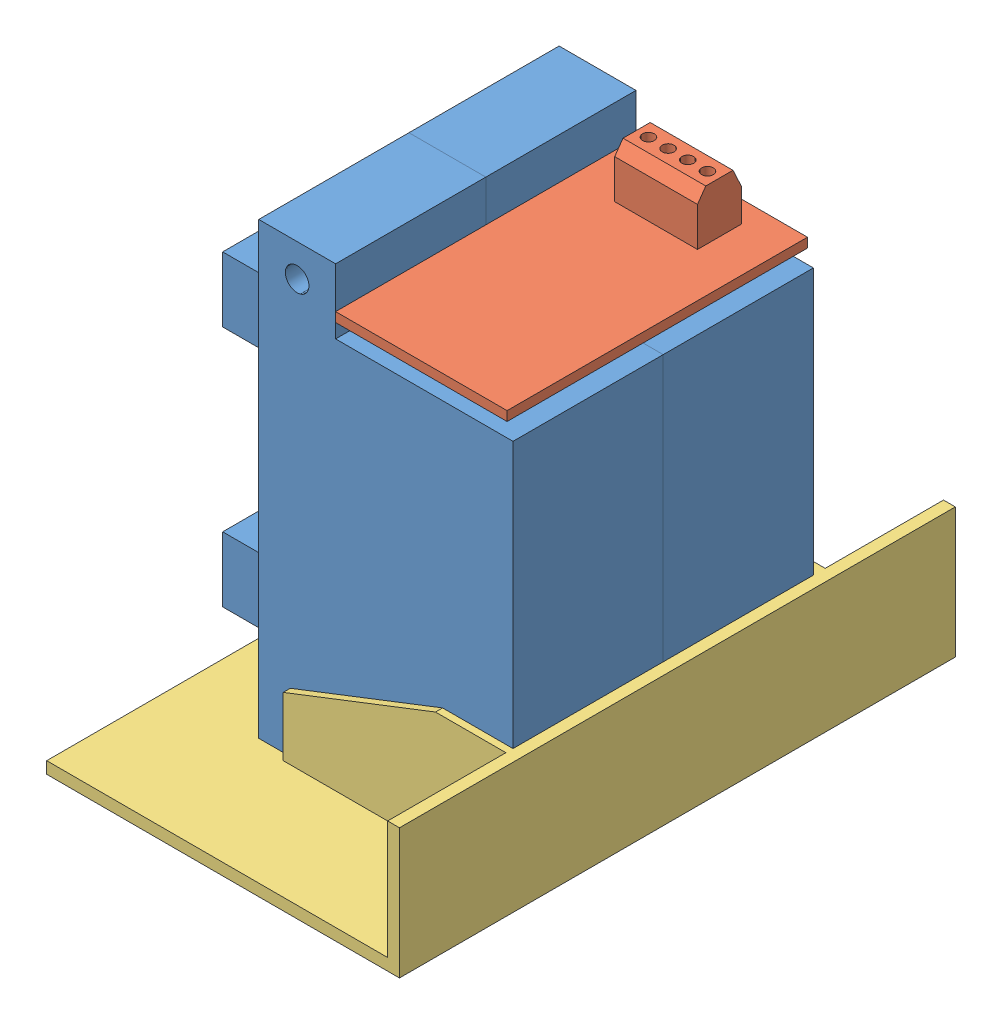
SolidWorks assembly 123SmartRelay, configuration Predeterminado. Lengths in mm.
Overall size (59.66 79.6 94).
4 component instances, 3 part files, 9 mates.
Components (placement in the parent):
- Relay200A-1: Relay200A [Predeterminado] at origin size (53.3 76 25.4)
- Relay200A-2: Relay200A [Predeterminado] at (0 0 -25.4) size (53.3 76 25.4)
- PCB_relays-1: PCB_relays [Predeterminado] at (27.5 67.4 -12.7) size (29 10.2 50.8)
- base relay-1: base relay [Predeterminado] at (43 0 -13.1) x (0 0 -1) z (1 0 0) size (94 22 59.66)
Mates (geometry in assembly coordinates):
- Coincidente1: coincident: plane of Relay200A-1 through (43 0 12.7) normal (1 0 0); plane of Relay200A-2 through (43 0 -12.7) normal (1 0 0)
- Coincidente2: coincident: plane of Relay200A-1 through (0 0 -12.7) normal (0 0 -1); plane of Relay200A-2 through (0 0 -12.7) normal (0 0 1)
- Coincidente3: coincident aligned: plane of Relay200A-1 through (0 0 12.7) normal (0 -1 0); plane of Relay200A-2 through (0 0 -12.7) normal (0 -1 0)
- Coincidente4: coincident: plane of Relay200A-1 through (13 65 12.7) normal (1 0 0); plane of PCB_relays-1 through (13 72.4566 -38.1) normal (-1 0 0)
- Ancho1: width: plane of Relay200A-1 through (0 0 12.7) normal (0 0 1); plane of PCB_relays-1 through (0 0 -38.1) normal (0 0 -1); plane of Relay200A-2 through (13 69 12.7) normal (0 0 1); plane of PCB_relays-1 through (13 69 -38.1) normal (0 0 -1)
- Distancia1: distance = 4 mm aligned: plane of PCB_relays-1 through (27.5 69 -12.7) normal (0 1 0); plane of Relay200A-2 through (13 65 -12.7) normal (0 1 0)
- Coincidente5: coincident: plane of Relay200A-1 through (0 0 12.7) normal (0 -1 0); plane of base relay-1 through (43 0 -13.1) normal (0 1 0)
- Coincidente6: coincident: plane of Relay200A-2 through (43 0 -12.7) normal (1 0 0); plane of base relay-1 through (43 0 -13.1) normal (-1 0 0)
- Coincidente7: coincident anti-aligned: plane of Relay200A-2 through (0 0 -38.1) normal (0 0 -1); plane of base relay-1 through (43 -61.4144 -38.1) normal (0 0 1)
